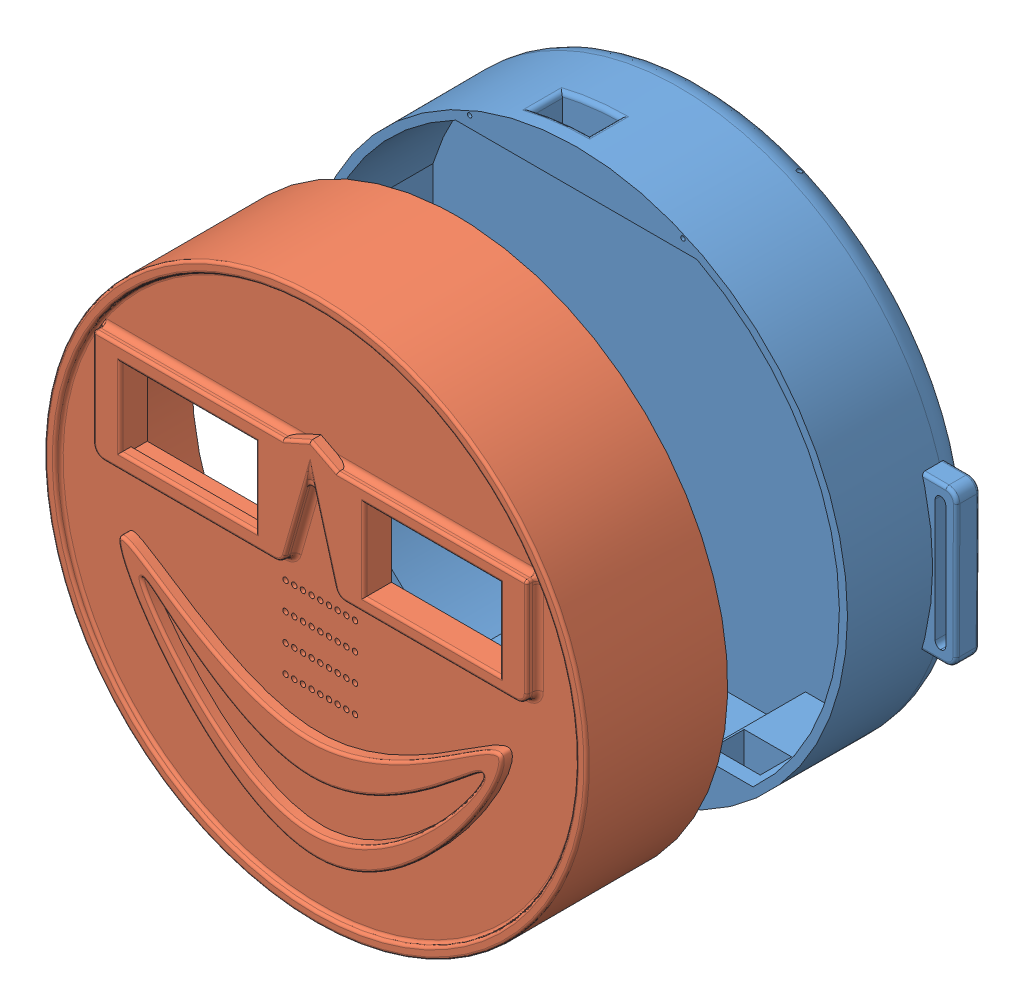
SolidWorks assembly Assembly_case, configuration Default. Lengths in mm.
Overall size (108.81 100.01 77.9).
2 component instances, 2 part files, 2 mates.
Components (placement in the parent):
- Smile_bottomd-1: Smile_bottomd [Default] at (-58.9461 -3.2823 120.3878) size (108.81 100 25.32)
- Smile_Topd-1: Smile_Topd [Default] at (-58.9461 -3.2823 190.4668) x (1 -0.000098 0) z (0.000098 1 0) size (100 30.81 100)
Mates (geometry in assembly coordinates):
- Concentric4: concentric aligned: circle of Smile_bottomd-1; circle of Smile_Topd-1
- Concentric7: concentric aligned: circle of Smile_bottomd-1; circle of Smile_Topd-1
